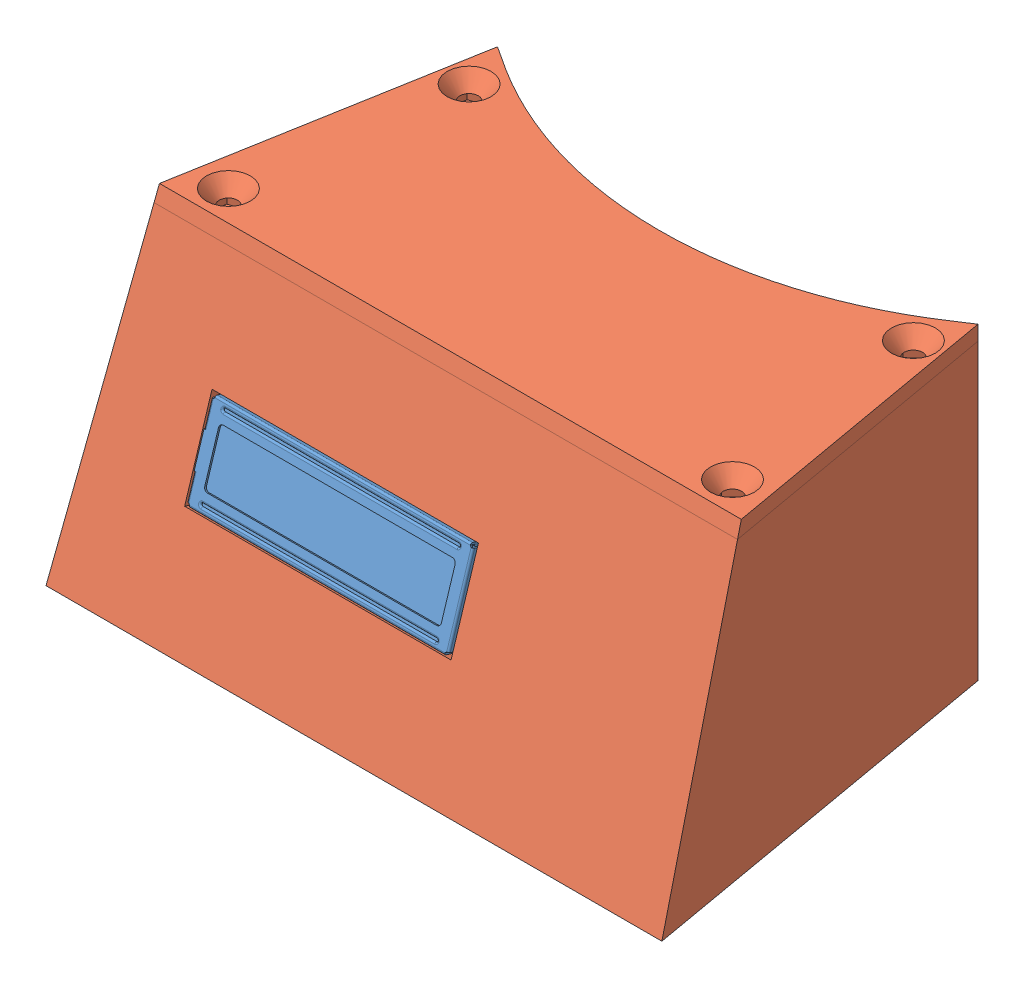
SolidWorks assembly Assem1, configuration Default. Lengths in mm.
Overall size (167.61 84.05 112.52).
4 component instances, 4 part files, 5 mates.
Components (placement in the parent):
- DFRobot_1602_LCD-1: DFRobot_1602_LCD [Default] at (66.2551 110.2232 52.8933) x (1 0 0) z (0 -0.95448 0.298275) size (80 10.64 36)
- SousVide-1: SousVide [Default] at (84.1728 67.8913 -8.9417) x (0 0 1) z (-1 0 0) size (112.52 84.05 167.61)
- Relay Board-1: Relay Board [Default] at (109.0349 101.8913 -0.2164) x (1 0 0) z (0 -1 0) size (67.5 20.1 60)
- Main Board-1: Main Board [Default] at (74.6288 92.8913 34.7348) x (1 0 0) z (0 1 0) size (77.21 24.02 42)
Mates (geometry in assembly coordinates):
- Parallel1: parallel anti-aligned: line of DFRobot_1602_LCD-1 through (99.4996 96.2621 60.4574) axis (-1 0 0); line of SousVide-1 through (29.1496 96.5257 61.3008) axis (1 0 0)
- Coincident4: coincident anti-aligned: plane of DFRobot_1602_LCD-1 through (29.9996 94.9199 56.1623) normal (0 -0.95448 0.298275); plane of SousVide-1 through (29.1496 72.4581 -15.7155) normal (0 0.95448 -0.298275)
- Coincident5: coincident anti-aligned: plane of DFRobot_1602_LCD-1 through (29.1496 117.0161 49.2572) normal (-1 0 0); plane of SousVide-1 through (29.1496 96.3201 -23.1724) normal (1 0 0)
- Coincident6: coincident anti-aligned: plane of SousVide-1 through (84.1323 71.8913 -12.9417) normal (0 1 0); plane of Relay Board-1 through (75.2849 71.8913 1.3836) normal (0 -1 0)
- Coincident7: coincident anti-aligned: plane of SousVide-1 through (84.1323 71.8913 -12.9417) normal (0 1 0); plane of Main Board-1 through (36.0238 71.8913 33.1348) normal (0 -1 0)
